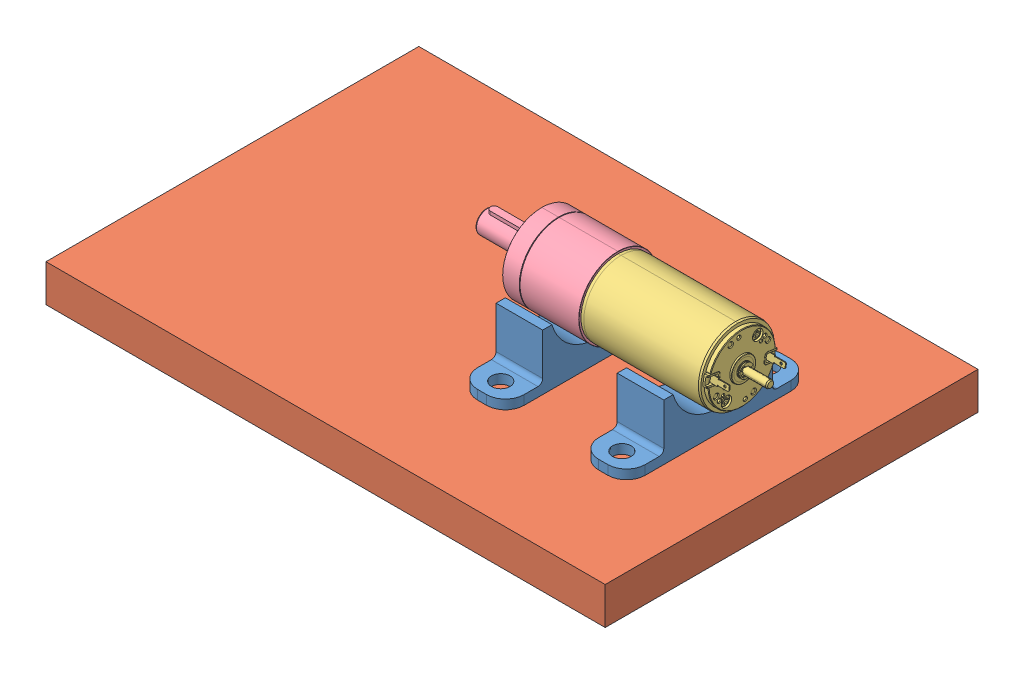
SolidWorks assembly experimento, configuration Valor predeterminado. Lengths in mm.
Overall size (300 77.66 200).
5 component instances, 4 part files, 8 mates.
Components (placement in the parent):
- suporte-1: suporte [Valor predeterminado] at (65.7938 79.0048 105.4427) x (0 0 -1) z (1 0 0) size (98.2 30 25)
- base-1: base [Valor predeterminado] at (-17.449 42.3485 54.8508) x (1 0 0) z (0 -1 0) size (300 200 20)
- 148866_RE40_GB_150W_KL_2WE.stp-1: 148866_RE40_GB_150W_KL_2WE.stp [Valor predeterminado] at (32.7557 79.0048 105.4427) size (106.6 40 40)
- 203113_GP42C-1st.stp-1: 203113_GP42C-1st.stp [Valor predeterminado] at (-3.8443 79.0048 105.4427) size (70.5 42 42)
- suporte-2: suporte [Valor predeterminado] at (0.7938 79.0048 105.4427) x (0 0 -1) z (1 0 0) size (98.2 30 25)
Mates (geometry in assembly coordinates):
- Coincidente1: coincident anti-aligned: plane of suporte-1 through (90.7938 42.3485 76.3451) normal (0 -1 0); plane of base-1 through (-17.449 42.3485 54.8508) normal (0 1 0)
- Coincidente4: coincident anti-aligned: plane of 148866_RE40_GB_150W_KL_2WE.stp-1 through (32.7557 79.0048 105.4427) normal (-1 0 0); plane of 203113_GP42C-1st.stp-1 through (32.7557 79.0048 105.4427) normal (1 0 0)
- Coincidente5: coincident anti-aligned: plane of base-1 through (-17.449 42.3485 54.8508) normal (0 1 0); plane of suporte-2 through (25.7938 42.3485 76.3451) normal (0 -1 0)
- Coincidente6: coincident aligned: line of suporte-1 through (90.7938 72.3485 76.3451) axis (-1 0 0); line of suporte-2 through (25.7938 72.3485 76.3451) axis (-1 0 0)
- Concêntrico1: concentric aligned: circle of suporte-1; circle of 148866_RE40_GB_150W_KL_2WE.stp-1
- Concêntrico2: concentric aligned: circle of suporte-1; circle of 203113_GP42C-1st.stp-1
- Distância2: distance = 50 mm: line of suporte-1 through (90.7938 72.3485 76.3451) axis (0 0 1); line of base-1 through (130.7938 42.3485 5.9839) axis (0 0 1)
- Distância3: distance = 40 mm: line of suporte-2 through (25.7938 72.3485 76.3451) axis (0 0 1); line of suporte-1 through (65.7938 72.3485 76.3451) axis (0 0 1)
